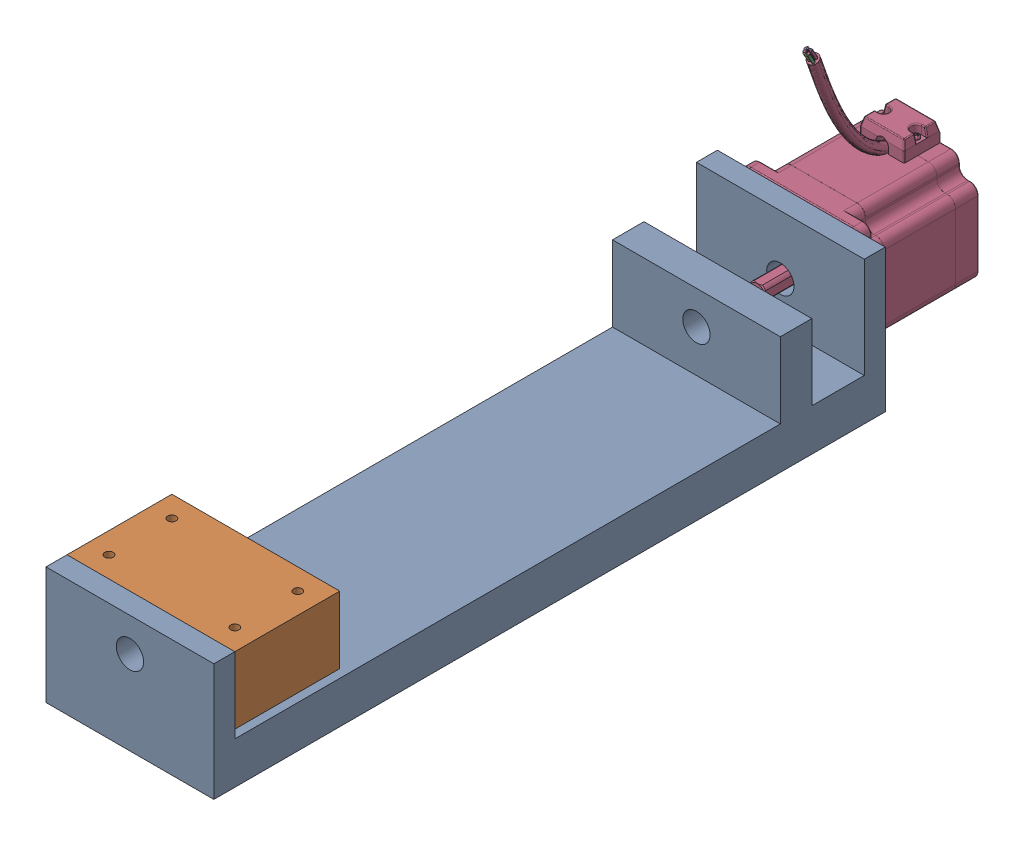
SolidWorks assembly Z Axis Stage, configuration Default. Lengths in mm.
Overall size (80 127.94 389.5).
3 component instances, 3 part files, 6 mates.
Components (placement in the parent):
- Base-1: Base [Default] at (32.7262 -12.9333 -170.4741) x (-1 0 0) z (0 0 -1) size (80 68 320)
- Block-1: Block [Default] at (-47.2738 11.0667 139.5259) size (80 32 50)
- Nema23-1: Nema23 [Default] at (-7.2738 27.0667 -226.4741) size (57.02 116.45 90.5)
Mates (geometry in assembly coordinates):
- Concentric1: concentric aligned: cylinder of Base-1 through (-7.2738 27.0667 -170.4741) axis (0 0 1) radius 6.5; cylinder of Block-1 through (-7.2738 27.0667 89.5259) axis (0 0 1) radius 6.5
- Parallel1: parallel anti-aligned: plane of Base-1 through (-47.2738 7.0667 -170.4741) normal (0 1 0); plane of Block-1 through (-47.2738 11.0667 139.5259) normal (0 -1 0)
- LimitDistance1: limit distance = 0 mm anti-aligned: plane of Block-1 through (-47.2738 43.0667 139.5259) normal (0 0 1); plane of Base-1 through (-47.2738 -12.9333 139.5259) normal (0 0 -1)
- Concentric2: concentric aligned: cylinder of Base-1 through (-7.2738 27.0667 -170.4741) axis (0 0 1) radius 6.5; cylinder of Nema23-1 through (-7.2738 27.0667 -170.4741) axis (0 0 1) radius 5
- Parallel2: parallel aligned: plane of Base-1 through (-47.2738 55.0667 -170.4741) normal (0 1 0); plane of Nema23-1 through (21.2262 55.5667 -170.4741) normal (0 1 0)
- Coincident4: coincident anti-aligned: plane of Base-1 through (-47.2738 -12.9333 -170.4741) normal (0 0 -1); plane of Nema23-1 through (-7.2738 27.0667 -170.4741) normal (0 0 1)
